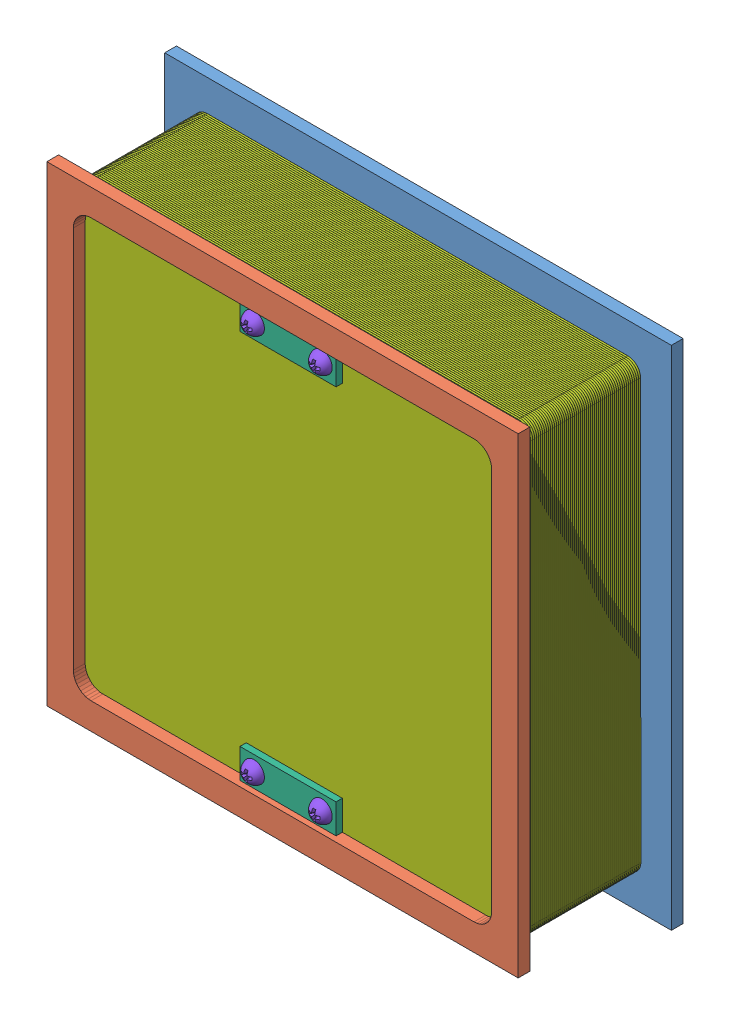
SolidWorks assembly Full_MT_Assembly, configuration Default. Lengths in mm.
Overall size (86 86 25.67).
25 component instances, 8 part files, 50 mates.
Components (placement in the parent):
- AirCoreBase-2: AirCoreBase [Default] at (-9.6264 88.2933 66.2568) x (1 0 0) z (0 -1 0) size (86 2.09 86)
- AirCoreSide-2: AirCoreSide [Default] at (-9.6264 88.2933 64.2568) x (1 0 0) z (0 -1 0) size (80 23.15 80)
- RodHat_v4-2: RodHat_v4 [Default] at (34.3736 13.7933 80.8268) x (1 0 0) z (0 1 0) size (16.31 5.11 5)
- RodHat_v4-3: RodHat_v4 [Default] at (34.3736 79.7933 80.8268) x (1 0 0) z (0 1 0) size (16.31 5.11 5)
- RodHat_v4-4: RodHat_v4 [Default] at (64.8736 44.2933 70.7568) x (0 1 0) z (-1 0 0) size (16.31 5.11 5)
- RodHat_v4-5: RodHat_v4 [Default] at (-1.1263 44.2933 70.7568) x (0 1 0) z (-1 0 0) size (16.31 5.11 5)
- Rod_Spiral_Assembly-1: Rod_Spiral_Assembly [Default] at (34.3736 8.7933 83.3268) size (8.7 71 7.53)
  - TorqueRod-1: TorqueRod [Default] at origin size (6.73 71 6.73)
  - RodSpiral-1: RodSpiral [Default] at (0 66 0) x (0 0 1) z (0 -1 0) size (7.53 8.7 61.32)
- Rod_Spiral_Assembly-3: Rod_Spiral_Assembly [Default] at (69.8736 44.2933 73.2568) x (0 0 1) z (0 -1 0) size (8.7 71 7.53)
  - TorqueRod-1: TorqueRod [Default] at origin size (6.73 71 6.73)
  - RodSpiral-1: RodSpiral [Default] at (0 66 0) x (0 0 1) z (0 -1 0) size (7.53 8.7 61.32)
- RodHatTop-1: RodHatTop [Default] at (34.3736 8.7933 85.8268) x (1 0 0) z (0 -1 0) size (16.31 5 5)
- RodHatTop-3: RodHatTop [Default] at (3.8737 44.2933 75.7568) x (0 1 0) z (1 0 0) size (16.31 5 5)
- RodHatTop-4: RodHatTop [Default] at (69.8736 44.2933 75.7568) x (0 1 0) z (1 0 0) size (16.31 5 5)
- RodHatTop-5: RodHatTop [Default] at (34.3736 79.7933 85.8268) x (-1 0 0) z (0 1 0) size (16.31 5 5)
- AirCoreSpiral-1: AirCoreSpiral [Default] at (34.3736 44.2933 66.2568) size (75.7 75.86 21.34)
- round head screw_ai-1: round head screw_ai [CR-RHMS 0.073-72x0.125x0.125-N] at (40.1286 11.2933 89.8762) x (0 0 -1) z (1 0 0) size (4.68 3.51 3.51)
- round head screw_ai-4: round head screw_ai [CR-RHMS 0.073-72x0.125x0.125-N] at (28.6186 11.2933 89.8762) x (0 0 -1) z (1 0 0) size (4.68 3.51 3.51)
- round head screw_ai-5: round head screw_ai [CR-RHMS 0.073-72x0.125x0.125-N] at (1.3737 38.5383 79.8062) x (0 0 -1) z (1 0 0) size (4.68 3.51 3.51)
- round head screw_ai-6: round head screw_ai [CR-RHMS 0.073-72x0.125x0.125-N] at (1.3737 50.0483 79.8062) x (0 0 -1) z (1 0 0) size (4.68 3.51 3.51)
- round head screw_ai-7: round head screw_ai [CR-RHMS 0.073-72x0.125x0.125-N] at (28.6186 77.2933 89.8762) x (0 0 -1) z (1 0 0) size (4.68 3.51 3.51)
- round head screw_ai-8: round head screw_ai [CR-RHMS 0.073-72x0.125x0.125-N] at (40.1286 77.2933 89.8762) x (0 0 -1) z (1 0 0) size (4.68 3.51 3.51)
- round head screw_ai-10: round head screw_ai [CR-RHMS 0.073-72x0.125x0.125-N] at (67.3736 50.0483 79.8062) x (0 0 -1) z (1 0 0) size (4.68 3.51 3.51)
- round head screw_ai-11: round head screw_ai [CR-RHMS 0.073-72x0.125x0.125-N] at (67.3736 38.5383 79.8062) x (0 0 -1) z (1 0 0) size (4.68 3.51 3.51)
Mates (geometry in assembly coordinates):
- Coincident1: coincident anti-aligned: plane of AirCoreBase-2 through (-9.6264 88.2933 66.2568) normal (0 0 1); plane of AirCoreSide-2 through (-9.6264 88.2933 66.2568) normal (0 0 -1)
- Distance2: distance = 5.5 mm aligned: plane of AirCoreSide-2 through (71.8737 6.7933 66.2568) normal (1 0 0); plane of AirCoreBase-2 through (77.3737 1.2933 64.2568) normal (1 0 0)
- Distance3: distance = 5.5 mm aligned: plane of AirCoreSide-2 through (-3.1263 6.7933 66.2568) normal (0 -1 0); plane of AirCoreBase-2 through (-8.6264 1.2933 64.2568) normal (0 -1 0)
- Coincident4: coincident anti-aligned: plane of AirCoreSide-2 through (-9.6264 0.2933 78.3268) normal (0 0 1); plane of RodHat_v4-2 through (26.2186 8.7933 78.3268) normal (0 0 -1)
- Coincident6: coincident aligned: plane of AirCoreSide-2 through (26.2186 13.7933 78.3268) normal (0 1 0); plane of RodHat_v4-2 through (34.3736 13.7933 80.8268) normal (0 1 0)
- Coincident7: coincident: point of AirCoreSide-2; point of RodHat_v4-2
- Coincident8: coincident anti-aligned: plane of AirCoreSide-2 through (-9.6264 88.2933 78.3268) normal (0 0 1); plane of RodHat_v4-3 through (26.2186 74.7933 78.3268) normal (0 0 -1)
- Coincident9: coincident aligned: plane of AirCoreSide-2 through (26.2186 74.7933 78.3268) normal (0 -1 0); plane of RodHat_v4-3 through (34.3736 74.7933 80.8268) normal (0 -1 0)
- Coincident10: coincident: point of AirCoreSide-2; point of RodHat_v4-3
- Coincident11: coincident anti-aligned: plane of AirCoreSide-2 through (78.3737 88.2933 68.2568) normal (0 0 1); plane of RodHat_v4-4 through (69.8736 36.1383 68.2568) normal (0 0 -1)
- Coincident12: coincident aligned: plane of AirCoreSide-2 through (64.8736 36.1383 68.2568) normal (-1 0 0); plane of RodHat_v4-4 through (64.8736 44.2933 70.7568) normal (-1 0 0)
- Coincident13: coincident: point of AirCoreSide-2; point of RodHat_v4-4
- Coincident14: coincident anti-aligned: plane of AirCoreSide-2 through (-9.6264 88.2933 68.2568) normal (0 0 1); plane of RodHat_v4-5 through (3.8737 36.1383 68.2568) normal (0 0 -1)
- Coincident15: coincident aligned: plane of AirCoreSide-2 through (3.8737 36.1383 68.2568) normal (1 0 0); plane of RodHat_v4-5 through (3.8737 44.2933 70.7568) normal (1 0 0)
- Coincident16: coincident: point of AirCoreSide-2; point of RodHat_v4-5
- Coincident17: coincident anti-aligned: plane of AirCoreSide-2 through (66.8737 8.7933 66.2568) normal (0 1 0); plane of Rod_Spiral_Assembly-1/TorqueRod-1 through (34.3736 8.7933 83.3268) normal (0 -1 0)
- Concentric1: concentric anti-aligned: circle of RodHat_v4-2; cylinder of Rod_Spiral_Assembly-1/TorqueRod-1 through (34.3736 79.7933 83.3268) axis (0 -1 0) radius 3.3655
- Coincident19: coincident anti-aligned: plane of AirCoreSide-2 through (69.8736 76.7933 66.2568) normal (-1 0 0); plane of Rod_Spiral_Assembly-3/TorqueRod-1 through (69.8736 44.2933 73.2568) normal (1 0 0)
- Concentric2: concentric anti-aligned: cylinder of RodHat_v4-5 through (3.8737 44.2933 73.2568) axis (-1 0 0) radius 3.355; cylinder of Rod_Spiral_Assembly-3/TorqueRod-1 through (-1.1264 44.2933 73.2568) axis (1 0 0) radius 3.3655
- Coincident20: coincident aligned: plane of RodHatTop-1 through (42.5286 13.7933 83.3268) normal (1 0 0); plane of RodHat_v4-2 through (42.5286 8.7933 83.3268) normal (1 0 0)
- Coincident21: coincident: point of RodHat_v4-2; point of RodHatTop-1
- Coincident22: coincident: point of RodHat_v4-2; point of RodHatTop-1
- Coincident23: coincident anti-aligned: plane of RodHat_v4-4 through (69.8736 36.1383 73.2568) normal (0 0 1); plane of RodHatTop-4 through (64.8736 36.1383 73.2568) normal (0 0 -1)
- Coincident24: coincident aligned: plane of RodHat_v4-4 through (64.8736 44.2933 70.7568) normal (-1 0 0); plane of RodHatTop-4 through (64.8736 44.2933 75.7568) normal (-1 0 0)
- Coincident25: coincident: point of RodHat_v4-4; point of RodHatTop-4
- Coincident26: coincident anti-aligned: plane of RodHat_v4-5 through (3.8737 36.1383 73.2568) normal (0 0 1); plane of RodHatTop-3 through (-1.1263 36.1383 73.2568) normal (0 0 -1)
- Coincident27: coincident aligned: plane of RodHat_v4-5 through (3.8737 52.4483 73.2568) normal (0 1 0); plane of RodHatTop-3 through (-1.1263 52.4483 73.2568) normal (0 1 0)
- Coincident28: coincident: point of RodHat_v4-5; point of RodHatTop-3
- Coincident29: coincident anti-aligned: plane of RodHat_v4-3 through (26.2186 74.7933 83.3268) normal (0 0 1); plane of RodHatTop-5 through (42.5286 74.7933 83.3268) normal (0 0 -1)
- Coincident30: coincident aligned: plane of RodHat_v4-3 through (34.3736 74.7933 80.8268) normal (0 -1 0); plane of RodHatTop-5 through (34.3736 74.7933 85.8268) normal (0 -1 0)
- Coincident31: coincident: point of RodHat_v4-3; point of RodHatTop-5
- Coincident32: coincident aligned: plane of AirCoreBase-2 through (-9.6264 88.2933 66.2568) normal (0 0 1); plane of AirCoreSpiral-1 through (34.3736 44.2933 66.2568) normal (0 0 1)
- Coincident33: coincident anti-aligned: plane of Rod_Spiral_Assembly-3 through (69.8736 44.2933 73.2568) normal (0 -1 0); plane of AirCoreSpiral-1 through (34.3736 44.2933 66.2568) normal (0 1 0)
- Coincident34: coincident aligned: plane of Rod_Spiral_Assembly-1 through (34.3736 8.7933 83.3268) normal (1 0 0); plane of AirCoreSpiral-1 through (34.3736 44.2933 66.2568) normal (1 0 0)
- Concentric31: concentric anti-aligned: cylinder of RodHatTop-1 through (40.1286 11.2933 88.3268) axis (0 0 -1) radius 1.4; cylinder of round head screw_ai-1 through (40.1286 11.2933 89.8762) axis (0 0 1) radius 0.9271
- Coincident351: coincident anti-aligned: plane of RodHatTop-1 through (26.2186 13.7933 88.3268) normal (0 0 1); plane of round head screw_ai-1 through (40.1286 12.2204 88.3268) normal (0 0 -1)
- Concentric41: concentric anti-aligned: cylinder of RodHatTop-1 through (28.6186 11.2933 88.3268) axis (0 0 -1) radius 1.4; cylinder of round head screw_ai-4 through (28.6186 11.2933 89.8762) axis (0 0 1) radius 0.9271
- Coincident371: coincident anti-aligned: plane of RodHatTop-1 through (26.2186 13.7933 88.3268) normal (0 0 1); plane of round head screw_ai-4 through (28.6186 12.2204 88.3268) normal (0 0 -1)
- Concentric51: concentric anti-aligned: cylinder of RodHatTop-3 through (1.3737 38.5383 78.2568) axis (0 0 -1) radius 1.4; cylinder of round head screw_ai-5 through (1.3737 38.5383 79.8062) axis (0 0 1) radius 0.9271
- Coincident381: coincident anti-aligned: plane of RodHatTop-3 through (-1.1263 36.1383 78.2568) normal (0 0 1); plane of round head screw_ai-5 through (1.3737 39.4654 78.2568) normal (0 0 -1)
- Concentric61: concentric anti-aligned: cylinder of RodHatTop-3 through (1.3737 50.0483 78.2568) axis (0 0 -1) radius 1.4; cylinder of round head screw_ai-6 through (1.3737 50.0483 79.8062) axis (0 0 1) radius 0.9271
- Coincident391: coincident anti-aligned: plane of RodHatTop-3 through (-1.1263 36.1383 78.2568) normal (0 0 1); plane of round head screw_ai-6 through (1.3737 50.9754 78.2568) normal (0 0 -1)
- Concentric71: concentric anti-aligned: cylinder of RodHatTop-5 through (28.6186 77.2933 88.3268) axis (0 0 -1) radius 1.4; cylinder of round head screw_ai-7 through (28.6186 77.2933 89.8762) axis (0 0 1) radius 0.9271
- Coincident401: coincident anti-aligned: plane of RodHatTop-5 through (42.5286 74.7933 88.3268) normal (0 0 1); plane of round head screw_ai-7 through (28.6186 78.2204 88.3268) normal (0 0 -1)
- Concentric81: concentric anti-aligned: cylinder of RodHatTop-5 through (40.1286 77.2933 88.3268) axis (0 0 -1) radius 1.4; cylinder of round head screw_ai-8 through (40.1286 77.2933 89.8762) axis (0 0 1) radius 0.9271
- Coincident411: coincident anti-aligned: plane of RodHatTop-5 through (42.5286 74.7933 88.3268) normal (0 0 1); plane of round head screw_ai-8 through (40.1286 78.2204 88.3268) normal (0 0 -1)
- Concentric91: concentric anti-aligned: cylinder of RodHatTop-4 through (67.3736 50.0483 78.2568) axis (0 0 -1) radius 1.4; cylinder of round head screw_ai-10 through (67.3736 50.0483 79.8062) axis (0 0 1) radius 0.9271
- Coincident421: coincident anti-aligned: plane of RodHatTop-4 through (64.8736 36.1383 78.2568) normal (0 0 1); plane of round head screw_ai-10 through (67.3736 50.9754 78.2568) normal (0 0 -1)
- Concentric101: concentric anti-aligned: cylinder of RodHatTop-4 through (67.3736 38.5383 78.2568) axis (0 0 -1) radius 1.4; cylinder of round head screw_ai-11 through (67.3736 38.5383 79.8062) axis (0 0 1) radius 0.9271
- Coincident431: coincident anti-aligned: plane of RodHatTop-4 through (64.8736 36.1383 78.2568) normal (0 0 1); plane of round head screw_ai-11 through (67.3736 39.4654 78.2568) normal (0 0 -1)
